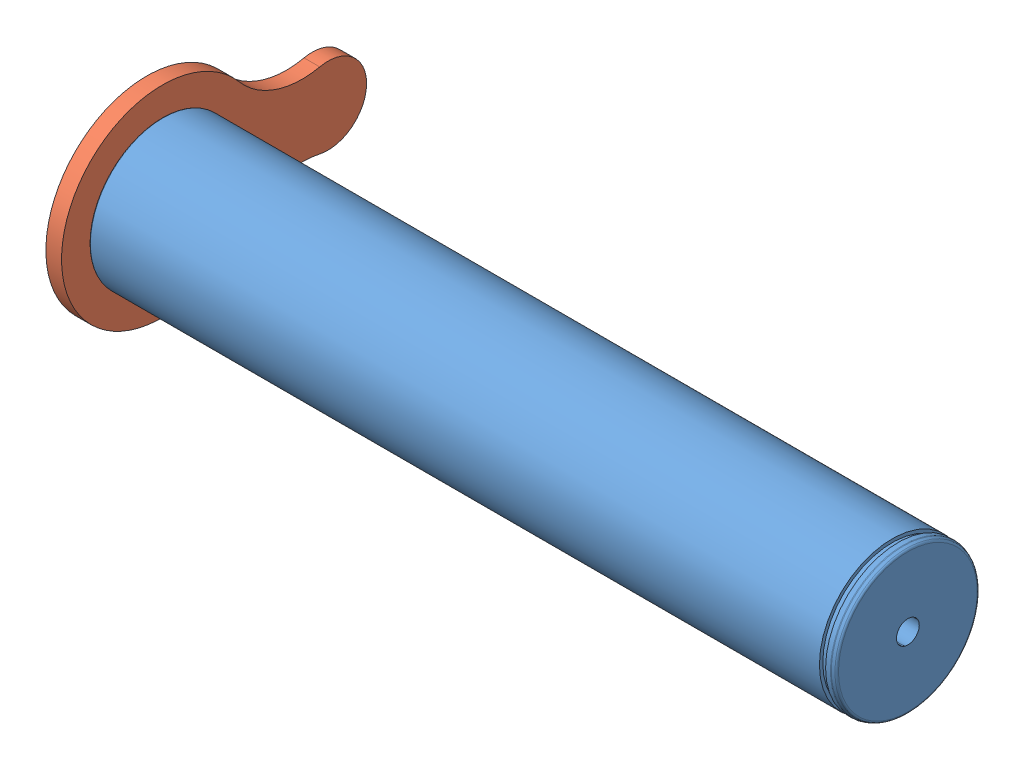
SolidWorks assembly 6344201, configuration Default. Lengths in mm.
Overall size (340 90 136.25).
3 component instances, 3 part files, 6 mates.
Components (placement in the parent):
- 6344202-1: 6344202 [Default] at origin size (338 65 65)
- 6342203-1: 6342203 [Default] at (-170 0 0) x (0 0 -1) z (1 0 0) size (136.25 90 7)
- Prop1_akselender-1: Prop1_akselender [Default] at (-171.138 0 0) (suppressed, hidden)
Mates (geometry in assembly coordinates):
- Coincident5: coincident anti-aligned: plane of 6344202-1 through (-163 32.1 0) normal (-1 0 0); plane of 6342203-1 through (-163 26.3702 -68.2248) normal (1 0 0)
- Concentric3: concentric aligned: cylinder of 6344202-1 through (-168 0 0) axis (-1 0 0) radius 28; cylinder of 6342203-1 through (-163 0 0) axis (-1 0 0) radius 28.25
- Parallel3: parallel aligned: plane of 6342203-1 through (-170 0 0) normal (0 1 0); plane of assembly through (0 0 0) normal (0 1 0)
- Concentric4: concentric aligned: cylinder of 6344202-1 through (-168 0 0) axis (-1 0 0) radius 5.1; cylinder of assembly through (-171.138 0 0) axis (-1 0 0) radius 4
- Tangent2: tangent: plane of assembly through (-170 26.3702 -68.2248) normal (-1 0 0)
- Parallel4: parallel: plane of ?; plane of assembly through (0 0 0) normal (0 0 1)
